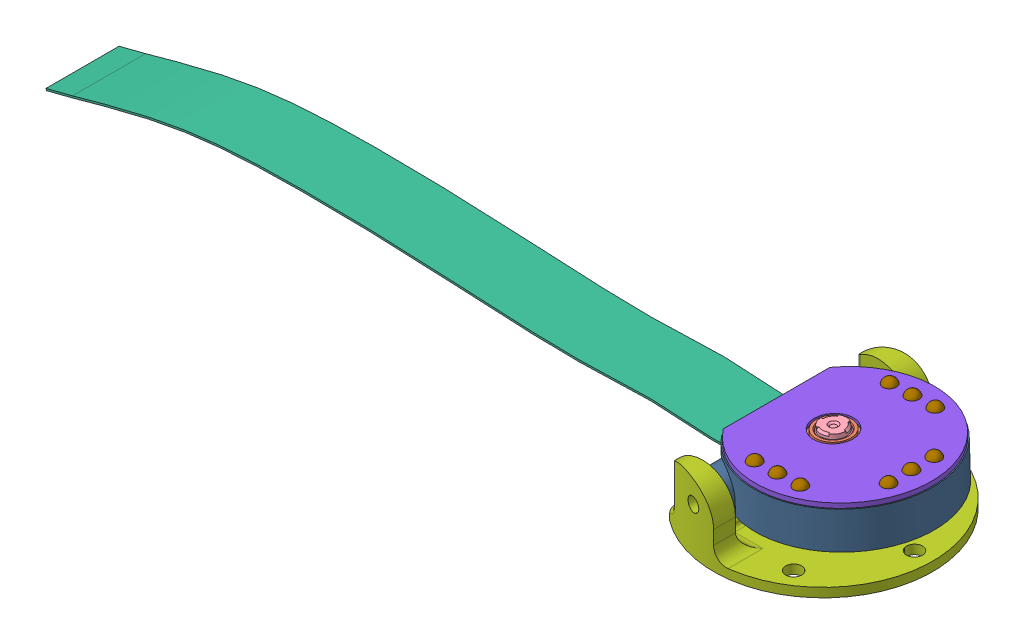
SolidWorks assembly birdcamv2.1, configuration Default. Lengths in mm.
Overall size (213.02 136.49 119.2).
20 component instances, 10 part files, 35 mates.
Components (placement in the parent):
- RasPi_Camera-1: RasPi_Camera [FOV] at (2.4203 12.3234 0) x (0 0 -1) z (0.999337 0.036413 0) size (119.2 126.8 208.54)
  - OVA5647-1: OVA5647 [FOV] at origin size (119.2 123.21 87.35)
    - OVA5647-1: OVA5647 [Standard] at (0.32 0 -0.175) size (8 0.68 8)
    - OVA5647_Housing-1: OVA5647_Housing [Standard] at origin size (8 3.95 8)
    - OVA5647_IR-Glas-1: OVA5647_IR-Glas [Standard] at (0 0.95 0) x (-1 0 0) z (0 0 1) size (6.3 0.35 6.3)
    - OVA5647_Lens-1: OVA5647_Lens [FOV] at (0 3.95 0) size (119.2 121.26 87.35)
    - OVA5647_Pigtail-1: OVA5647_Pigtail [Standard] at origin size (7.6 1.3 8.75)
  - RasPi_Camera_Board-1: RasPi_Camera_Board [Standard] at (0 -0.5517 0) x (-1 0 0) z (0 0 -1) size (25 7.57 179.36)
- cambasev21-1: cambasev21 [Default] at origin size (38.74 15.2 48)
- pokrov21-1: pokrov21 [Default] at (14.9321 12.2273 10.5) x (0 0 1) z (-0.999337 -0.036413 0) size (38 6.5 34)
- 3mmled-1: 3mmled [Default] at (-0.1162 13.28 -14.7843) x (-0.999337 -0.036413 0) z (0 0 -1) size (4.1 8.1 3.57)
- 3mmled-2: 3mmled [Default] at (4.8805 13.4621 -14.7843) x (-0.999337 -0.036413 0) z (0 0 -1) size (4.1 8.1 3.57)
- 3mmled-3: 3mmled [Default] at (9.8772 13.6441 -14.7843) x (-0.999337 -0.036413 0) z (0 0 -1) size (4.1 8.1 3.57)
- 3mmled-6: 3mmled [Default] at (19.4334 13.9923 -5) x (0 0 -1) z (0.999337 0.036413 0) size (4.1 8.1 3.57)
- 3mmled-7: 3mmled [Default] at (19.4334 13.9923 0) x (0 0 -1) z (0.999337 0.036413 0) size (4.1 8.1 3.57)
- 3mmled-8: 3mmled [Default] at (19.4334 13.9923 5) x (0 0 -1) z (0.999337 0.036413 0) size (4.1 8.1 3.57)
- 3mmled-9: 3mmled [Default] at (9.8772 13.6441 14.7843) x (0.999337 0.036413 0) z (0 0 1) size (4.1 8.1 3.57)
- 3mmled-10: 3mmled [Default] at (4.8805 13.4621 14.7843) x (0.999337 0.036413 0) z (0 0 1) size (4.1 8.1 3.57)
- 3mmled-11: 3mmled [Default] at (-0.1162 13.28 14.7843) x (0.999337 0.036413 0) z (0 0 1) size (4.1 8.1 3.57)
- obodv2-1: obodv2 [Default] at (5.0662 8.3655 0) x (0.999337 0.036413 0) z (0 0 1) size (34.25 8 38.5)
Mates (geometry in assembly coordinates):
- Coincident1: coordinate: point of cambasev21-1; point of assembly
- Coincident2: coincident anti-aligned: plane of RasPi_Camera-1/RasPi_Camera_Board-1 through (2.4404 11.7721 0) normal (-0.036413 0.999337 0); plane of pokrov21-1 through (4.9387 11.8631 0) normal (0.036413 -0.999337 0)
- Coincident4: coincident anti-aligned: plane of ?; plane of pokrov21-1
- Concentric2: concentric anti-aligned: cylinder of pokrov21-1 through (-0.2218 16.1781 -14.7843) axis (0.036413 -0.999337 0) radius 1.55; cylinder of 3mmled-1 through (-0.2655 17.3773 -14.7843) axis (-0.036413 0.999337 0) radius 1.5
- Parallel1: parallel anti-aligned: plane of pokrov21-1 through (-1.2912 13.2372 -12.9843) normal (0 0 -1); plane of 3mmled-1 through (1.8683 12.3517 -13.2843) normal (0 0 1)
- Coincident9: coincident anti-aligned: plane of pokrov21-1 through (-0.1162 13.28 -14.7843) normal (0.036413 -0.999337 0); plane of 3mmled-1 through (1.3828 13.3346 -14.7843) normal (-0.036413 0.999337 0)
- Parallel2: parallel anti-aligned: plane of pokrov21-1 through (-1.2912 13.2372 -12.9843) normal (0 0 -1); plane of 3mmled-2 through (6.865 12.5337 -13.2843) normal (0 0 1)
- Coincident10: coincident anti-aligned: plane of pokrov21-1 through (-0.1162 13.28 -14.7843) normal (0.036413 -0.999337 0); plane of 3mmled-2 through (6.3795 13.5167 -14.7843) normal (-0.036413 0.999337 0)
- Concentric3: concentric anti-aligned: cylinder of pokrov21-1 through (4.8805 13.4621 -14.7843) axis (0.036413 -0.999337 0) radius 2.15; cylinder of 3mmled-2 through (4.7312 17.5594 -14.7843) axis (-0.036413 0.999337 0) radius 1.5
- Parallel3: parallel anti-aligned: plane of pokrov21-1 through (-1.2912 13.2372 -12.9843) normal (0 0 -1); plane of 3mmled-3 through (11.8617 12.7158 -13.2843) normal (0 0 1)
- Coincident11: coincident anti-aligned: plane of pokrov21-1 through (-0.1162 13.28 -14.7843) normal (0.036413 -0.999337 0); plane of 3mmled-3 through (11.3762 13.6988 -14.7843) normal (-0.036413 0.999337 0)
- Concentric4: concentric anti-aligned: cylinder of pokrov21-1 through (9.8772 13.6441 -14.7843) axis (0.036413 -0.999337 0) radius 2.15; cylinder of 3mmled-3 through (9.7279 17.7414 -14.7843) axis (-0.036413 0.999337 0) radius 1.5
- Coincident14: coincident anti-aligned: plane of pokrov21-1 through (-0.1162 13.28 -14.7843) normal (0.036413 -0.999337 0); plane of 3mmled-6 through (19.4334 13.9923 -3.5) normal (-0.036413 0.999337 0)
- Concentric5: concentric anti-aligned: cylinder of pokrov21-1 through (19.3278 16.8904 -5) axis (0.036413 -0.999337 0) radius 1.55; cylinder of 3mmled-6 through (19.2841 18.0896 -5) axis (-0.036413 0.999337 0) radius 1.5
- Parallel7: parallel anti-aligned: plane of 3mmled-6 through (17.9708 12.9384 -3.0506) normal (-0.999337 -0.036413 0); plane of pokrov21-1 through (17.6346 13.9268 -6.1758) normal (0.999337 0.036413 0)
- Parallel8: parallel anti-aligned: plane of 3mmled-7 through (17.9708 12.9384 1.9494) normal (-0.999337 -0.036413 0); plane of pokrov21-1 through (17.6346 13.9268 -1.1758) normal (0.999337 0.036413 0)
- Coincident15: coincident anti-aligned: plane of pokrov21-1 through (-0.1162 13.28 -14.7843) normal (0.036413 -0.999337 0); plane of 3mmled-7 through (19.4334 13.9923 1.5) normal (-0.036413 0.999337 0)
- Concentric6: concentric anti-aligned: cylinder of pokrov21-1 through (19.3278 16.8904 0) axis (0.036413 -0.999337 0) radius 1.55; cylinder of 3mmled-7 through (19.2841 18.0896 0) axis (-0.036413 0.999337 0) radius 1.5
- Parallel9: parallel anti-aligned: plane of 3mmled-8 through (17.9708 12.9384 6.9494) normal (-0.999337 -0.036413 0); plane of pokrov21-1 through (17.6346 13.9268 3.8242) normal (0.999337 0.036413 0)
- Coincident16: coincident anti-aligned: plane of pokrov21-1 through (-0.1162 13.28 -14.7843) normal (0.036413 -0.999337 0); plane of 3mmled-8 through (19.4334 13.9923 6.5) normal (-0.036413 0.999337 0)
- Concentric7: concentric anti-aligned: cylinder of pokrov21-1 through (19.3278 16.8904 5) axis (0.036413 -0.999337 0) radius 1.55; cylinder of 3mmled-8 through (19.2841 18.0896 5) axis (-0.036413 0.999337 0) radius 1.5
- Coincident17: coincident anti-aligned: plane of pokrov21-1 through (-0.1162 13.28 -14.7843) normal (0.036413 -0.999337 0); plane of 3mmled-9 through (8.3782 13.5895 14.7843) normal (-0.036413 0.999337 0)
- Parallel10: parallel anti-aligned: plane of pokrov21-1 through (8.7022 13.6013 12.9843) normal (0 0 1); plane of 3mmled-9 through (7.9655 12.5738 13.2843) normal (0 0 -1)
- Concentric8: concentric anti-aligned: cylinder of pokrov21-1 through (9.7716 16.5422 14.7843) axis (0.036413 -0.999337 0) radius 1.55; cylinder of 3mmled-9 through (9.7279 17.7414 14.7843) axis (-0.036413 0.999337 0) radius 1.5
- Parallel11: parallel aligned: plane of pokrov21-1 through (-1.2912 13.2372 -12.9843) normal (0 0 -1); plane of 3mmled-10 through (2.9688 12.3918 13.2843) normal (0 0 -1)
- Coincident18: coincident anti-aligned: plane of pokrov21-1 through (-0.1162 13.28 -14.7843) normal (0.036413 -0.999337 0); plane of 3mmled-10 through (3.3815 13.4075 14.7843) normal (-0.036413 0.999337 0)
- Concentric9: concentric anti-aligned: cylinder of pokrov21-1 through (4.7749 16.3602 14.7843) axis (0.036413 -0.999337 0) radius 1.55; cylinder of 3mmled-10 through (4.7312 17.5594 14.7843) axis (-0.036413 0.999337 0) radius 1.5
- Parallel12: parallel aligned: plane of pokrov21-1 through (-1.2912 13.2372 -12.9843) normal (0 0 -1); plane of 3mmled-11 through (-2.0279 12.2097 13.2843) normal (0 0 -1)
- Coincident19: coincident anti-aligned: plane of pokrov21-1 through (-0.1162 13.28 -14.7843) normal (0.036413 -0.999337 0); plane of 3mmled-11 through (-1.6152 13.2254 14.7843) normal (-0.036413 0.999337 0)
- Concentric10: concentric anti-aligned: cylinder of pokrov21-1 through (-0.2218 16.1781 14.7843) axis (0.036413 -0.999337 0) radius 1.55; cylinder of 3mmled-11 through (-0.2655 17.3773 14.7843) axis (-0.036413 0.999337 0) radius 1.5
- Concentric11: concentric anti-aligned: cylinder of RasPi_Camera-1/OVA5647-1/OVA5647_Housing-1 through (2.2765 16.2708 0) axis (0.036413 -0.999337 0) radius 3.8; cylinder of pokrov21-1 through (2.2984 15.6695 0) axis (-0.036413 0.999337 0) radius 4.25
- Coincident22: coincident anti-aligned: plane of ?; plane of assembly through (0 0 0) normal (0 0 1)
- Concentric12: concentric aligned: cylinder of pokrov21-1 through (4.7749 16.3602 0) axis (0.036413 -0.999337 0) radius 18; cylinder of obodv2-1 through (4.8113 15.3608 0) axis (0.036413 -0.999337 0) radius 18.25
- Coincident24: coincident anti-aligned: plane of pokrov21-1 through (4.8113 15.3608 0) normal (0.036413 -0.999337 0); plane of obodv2-1 through (4.8113 15.3608 0) normal (-0.036413 0.999337 0)
- Concentric14: concentric anti-aligned: cylinder of cambasev21-1 through (-5 10 -24.001) axis (0 0 1) radius 1.5; cylinder of obodv2-1 through (-5 10 19.251) axis (0 0 -1) radius 1.5
